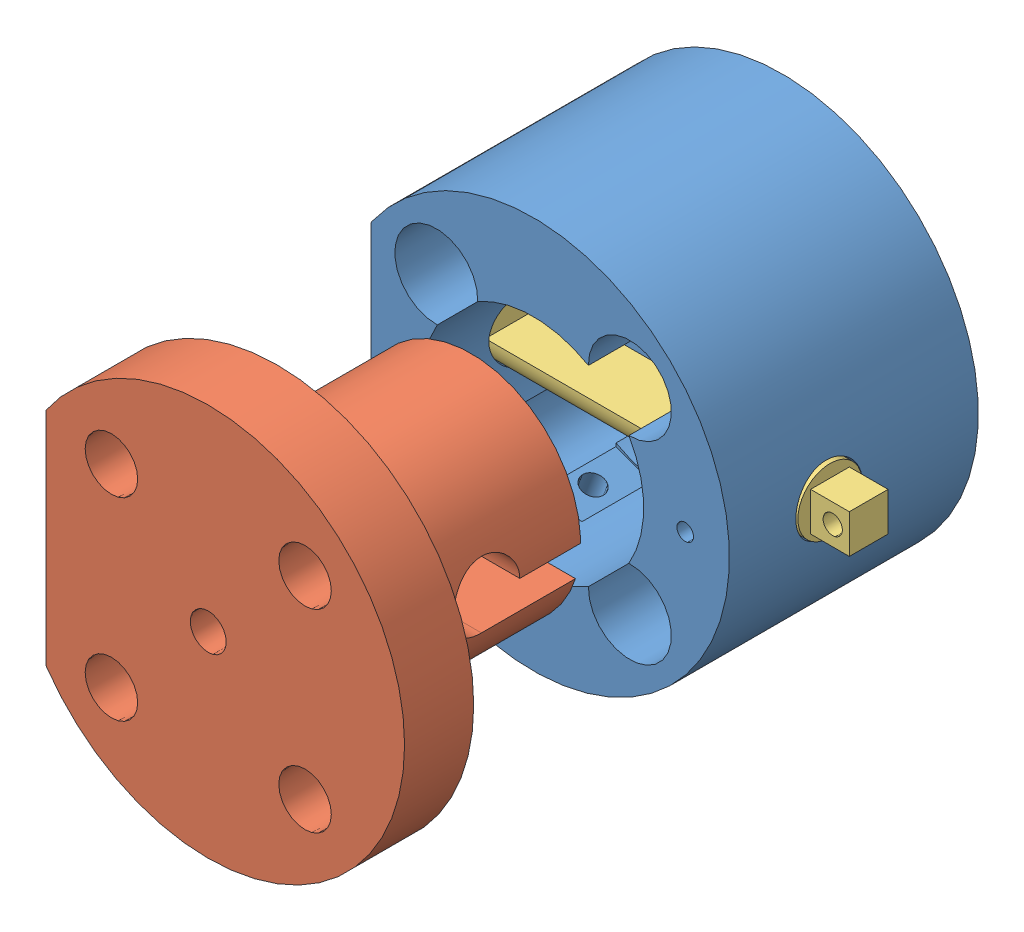
SolidWorks assembly Ensamblaje - base kuka, configuration Predeterminado. Lengths in mm.
Overall size (78.17 71 103.73).
3 component instances, 3 part files, 6 mates.
Components (placement in the parent):
- Base - Kuka-1: Base - Kuka [Predeterminado] at (2.8522 3.3828 0) size (71 71 45)
- Cople - kuka-1: Cople - kuka [Predeterminado] at (2.8522 3.3828 91.2298) x (0 1 0) z (0 0 -1) size (71 64.83 47.5)
- Pestillo - Kuka-1: Pestillo - Kuka [Predeterminado] at (6.0222 3.3828 22) x (0 0 -1) z (1 0 0) size (11.6 11.6 72)
Mates (geometry in assembly coordinates):
- Coincidente1: coincident aligned: plane of Base - Kuka-1 through (-26.4778 3.3828 40) normal (-1 0 0); plane of Cople - kuka-1 through (-26.4778 -16.6172 93.7298) normal (-1 0 0)
- Paralelo1: parallel aligned: line of Base - Kuka-1 through (-26.4778 23.3828 40) axis (0 -1 0); line of Cople - kuka-1 through (-26.4778 23.3828 86.2298) axis (0 -1 0)
- Concéntrica1: concentric anti-aligned: cylinder of Base - Kuka-1 through (2.8522 3.3828 40) axis (0 0 -1) radius 20; cylinder of Cople - kuka-1 through (2.8522 3.3828 51.2298) axis (0 0 1) radius 19.825
- Concéntrica2: concentric aligned: cylinder of Base - Kuka-1 through (38.3522 3.3828 22) axis (-1 0 0) radius 6; cylinder of Pestillo-1 through (38.5222 3.3828 22) axis (-1 0 0) radius 5.8
- Coincidente3: coincident anti-aligned: plane of Cople - kuka-1 through (-32.6478 3.3828 62.2298) normal (0 -1 0); plane of Pestillo-1 through (-17.9778 3.3828 27.8) normal (0 1 0)
- Coincidente4: coincident aligned: plane of Base - Kuka-1 through (-26.4778 3.3828 40) normal (-1 0 0); plane of Pestillo-1 through (-26.4778 3.3828 22) normal (-1 0 0)
